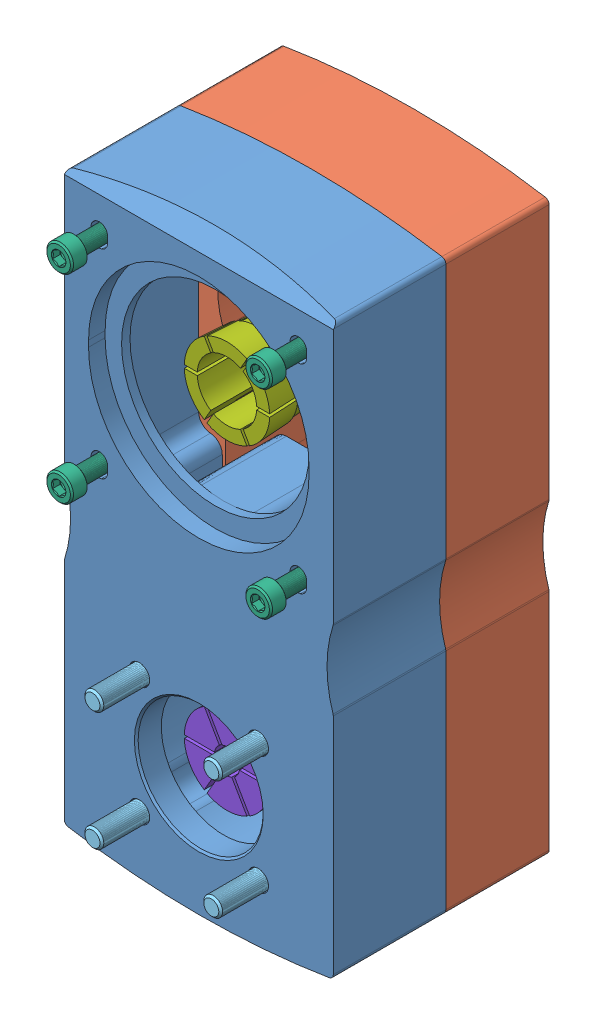
SolidWorks assembly 2802441 EAMM-U-86-D40-80P-102, configuration Default. Lengths in mm.
Overall size (86 188.5 84).
21 component instances, 8 part files, 30 mates.
Components (placement in the parent):
- 2799627 EAMM-U-86-D40-80P-102---(UT)-1: 2799627 EAMM-U-86-D40-80P-102---(UT) [Default] at (0 150.5 0) x (1 0 0) z (0 1 0) size (86 36 188.5)
- 1190018 EAMM-U-86-D40-___-188_5---(OT)-1: 1190018 EAMM-U-86-D40-___-188_5---(OT) [Default] at (0 150.5 -36) x (1 0 0) z (0 1 0) size (86 33 188.5)
- DIN-912 - M6x40(F)-1: DIN-912 - M6x40(F) [Default] at (36 -18 -62) x (1 0 0) z (0 1 0) size (10 46.29 10)
- DIN-912 - M6x40(F)-2: DIN-912 - M6x40(F) [Default] at (36 18 -62) x (1 0 0) z (0 1 0) size (10 46.29 10)
- DIN-912 - M6x40(F)-3: DIN-912 - M6x40(F) [Default] at (-36 -18 -62) x (1 0 0) z (0 1 0) size (10 46.29 10)
- DIN-912 - M6x40(F)-4: DIN-912 - M6x40(F) [Default] at (-36 18 -62) x (1 0 0) z (0 1 0) size (10 46.29 10)
- DIN-912 - M6x40(F)-5: DIN-912 - M6x40(F) [Default] at (0 143.5 -62) x (1 0 0) z (0 1 0) size (10 46.29 10)
- DIN 557 - M5-1: DIN 557 - M5 [Default] at (31.8198 134.3198 -4) x (0 0 -1) z (-0.707107 -0.707107 0) size (4 11.31 11.31)
- DIN 557 - M5-2: DIN 557 - M5 [Default] at (31.8198 70.6802 -4) x (0 0 -1) z (-0.707107 -0.707107 0) size (4 11.31 11.31)
- DIN 557 - M5-3: DIN 557 - M5 [Default] at (-31.8198 70.6802 -4) x (0 0 -1) z (-0.707107 -0.707107 0) size (4 11.31 11.31)
- DIN 557 - M5-4: DIN 557 - M5 [Default] at (-31.8198 134.3198 -4) x (0 0 -1) z (-0.707107 -0.707107 0) size (4 11.31 11.31)
- DIN-6912 - M6x18(F)-1: DIN-6912 - M6x18(F) [Default] at (19 19 -3) x (0 0 1) z (-1 0 0) size (22.29 10 10)
- DIN-6912 - M6x18(F)-2: DIN-6912 - M6x18(F) [Default] at (19 -19 -3) x (0 0 1) z (-1 0 0) size (22.29 10 10)
- DIN-6912 - M6x18(F)-3: DIN-6912 - M6x18(F) [Default] at (-19 19 -3) x (0 0 1) z (-1 0 0) size (22.29 10 10)
- DIN-6912 - M6x18(F)-4: DIN-6912 - M6x18(F) [Default] at (-19 -19 -3) x (0 0 1) z (-1 0 0) size (22.29 10 10)
- DIN-912 - M5x20(F)-1: DIN-912 - M5x20(F) [Default] at (31.8198 134.3198 8) x (1 0 0) z (0 -1 0) size (8.5 25.23 8.5)
- DIN-912 - M5x20(F)-2: DIN-912 - M5x20(F) [Default] at (31.8198 70.6802 8) x (1 0 0) z (0 -1 0) size (8.5 25.23 8.5)
- DIN-912 - M5x20(F)-3: DIN-912 - M5x20(F) [Default] at (-31.8198 70.6802 8) x (1 0 0) z (0 -1 0) size (8.5 25.23 8.5)
- DIN-912 - M5x20(F)-4: DIN-912 - M5x20(F) [Default] at (-31.8198 134.3198 8) x (1 0 0) z (0 -1 0) size (8.5 25.23 8.5)
- 2429535 EAMH-86-19-C27_3-1: 2429535 EAMH-86-19-C27_3 [Default] at (0 102.5 -49) x (0 0 1) z (-1 0 0) size (40.22 27.3 27.28)
- 2429531 EAMH-86-8-C27_3-1: 2429531 EAMH-86-8-C27_3 [Default] at (0 0 -49) x (0 0 1) z (-1 0 0) size (40.22 27.3 27.28)
Mates (geometry in assembly coordinates):
- Distance1: distance = 0 mm anti-aligned: plane of 2799627 EAMM-U-86-D40-80P-102---(UT)-1 through (0 150.5 -3) normal (0 0 -1); plane of DIN-6912 - M6x18(F)-1 through (19 19 -3) normal (0 0 1)
- Coincident1: coincident anti-aligned: line of 2799627 EAMM-U-86-D40-80P-102---(UT)-1 through (19 19 -50) axis (0 0 1); line of DIN-6912 - M6x18(F)-1 through (19 19 77.9) axis (0 0 -1)
- Angle3: planar angle = 0 rad aligned: plane of DIN-6912 - M6x18(F)-1 through (19 19 -3) normal (1 0 0); plane of 2799627 EAMM-U-86-D40-80P-102---(UT)-1 through (19 150.5 0) normal (1 0 0)
- Distance2: distance = 0 mm anti-aligned: plane of 2799627 EAMM-U-86-D40-80P-102---(UT)-1 through (0 150.5 -3) normal (0 0 -1); plane of DIN-6912 - M6x18(F)-2 through (19 -19 -3) normal (0 0 1)
- Coincident2: coincident anti-aligned: line of 2799627 EAMM-U-86-D40-80P-102---(UT)-1 through (19 -19 -50) axis (0 0 1); line of DIN-6912 - M6x18(F)-2 through (19 -19 77.9) axis (0 0 -1)
- Angle6: planar angle = 0 rad aligned: plane of DIN-6912 - M6x18(F)-2 through (19 -19 -3) normal (1 0 0); plane of 2799627 EAMM-U-86-D40-80P-102---(UT)-1 through (19 150.5 0) normal (1 0 0)
- Distance3: distance = 0 mm anti-aligned: plane of 2799627 EAMM-U-86-D40-80P-102---(UT)-1 through (0 150.5 -3) normal (0 0 -1); plane of DIN-6912 - M6x18(F)-3 through (-19 19 -3) normal (0 0 1)
- Coincident3: coincident anti-aligned: line of 2799627 EAMM-U-86-D40-80P-102---(UT)-1 through (-19 19 -50) axis (0 0 1); line of DIN-6912 - M6x18(F)-3 through (-19 19 77.9) axis (0 0 -1)
- Angle9: planar angle = 0 rad aligned: plane of DIN-6912 - M6x18(F)-3 through (-19 19 -3) normal (1 0 0); plane of 2799627 EAMM-U-86-D40-80P-102---(UT)-1 through (-19 150.5 0) normal (1 0 0)
- Distance4: distance = 0 mm anti-aligned: plane of 2799627 EAMM-U-86-D40-80P-102---(UT)-1 through (0 150.5 -3) normal (0 0 -1); plane of DIN-6912 - M6x18(F)-4 through (-19 -19 -3) normal (0 0 1)
- Coincident4: coincident anti-aligned: line of 2799627 EAMM-U-86-D40-80P-102---(UT)-1 through (-19 -19 -50) axis (0 0 1); line of DIN-6912 - M6x18(F)-4 through (-19 -19 77.9) axis (0 0 -1)
- Angle12: planar angle = 0 rad aligned: plane of DIN-6912 - M6x18(F)-4 through (-19 -19 -3) normal (1 0 0); plane of 2799627 EAMM-U-86-D40-80P-102---(UT)-1 through (-19 150.5 0) normal (1 0 0)
- Distance5: distance = 0 mm anti-aligned: plane of 2799627 EAMM-U-86-D40-80P-102---(UT)-1 through (0 150.5 8) normal (0 0 -1); plane of DIN-912 - M5x20(F)-1 through (31.8198 134.3198 8) normal (0 0 1)
- Coincident5: coincident anti-aligned: line of 2799627 EAMM-U-86-D40-80P-102---(UT)-1 through (31.8198 134.3198 -50) axis (0 0 1); line of DIN-912 - M5x20(F)-1 through (31.8198 134.3198 58) axis (0 0 -1)
- Angle15: planar angle = 0 rad aligned: plane of DIN-912 - M5x20(F)-1 through (31.8198 134.3198 8) normal (1 0 0); plane of 2799627 EAMM-U-86-D40-80P-102---(UT)-1 through (31.8198 150.5 0) normal (1 0 0)
- Distance6: distance = 0 mm anti-aligned: plane of 2799627 EAMM-U-86-D40-80P-102---(UT)-1 through (0 150.5 8) normal (0 0 -1); plane of DIN-912 - M5x20(F)-2 through (31.8198 70.6802 8) normal (0 0 1)
- Coincident6: coincident anti-aligned: line of 2799627 EAMM-U-86-D40-80P-102---(UT)-1 through (31.8198 70.6802 -50) axis (0 0 1); line of DIN-912 - M5x20(F)-2 through (31.8198 70.6802 58) axis (0 0 -1)
- Angle18: planar angle = 0 rad aligned: plane of DIN-912 - M5x20(F)-2 through (31.8198 70.6802 8) normal (1 0 0); plane of 2799627 EAMM-U-86-D40-80P-102---(UT)-1 through (31.8198 150.5 0) normal (1 0 0)
- Distance7: distance = 0 mm anti-aligned: plane of 2799627 EAMM-U-86-D40-80P-102---(UT)-1 through (0 150.5 8) normal (0 0 -1); plane of DIN-912 - M5x20(F)-3 through (-31.8198 70.6802 8) normal (0 0 1)
- Coincident7: coincident anti-aligned: line of 2799627 EAMM-U-86-D40-80P-102---(UT)-1 through (-31.8198 70.6802 -50) axis (0 0 1); line of DIN-912 - M5x20(F)-3 through (-31.8198 70.6802 58) axis (0 0 -1)
- Angle21: planar angle = 0 rad aligned: plane of DIN-912 - M5x20(F)-3 through (-31.8198 70.6802 8) normal (1 0 0); plane of 2799627 EAMM-U-86-D40-80P-102---(UT)-1 through (-31.8198 150.5 0) normal (1 0 0)
- Distance8: distance = 0 mm anti-aligned: plane of 2799627 EAMM-U-86-D40-80P-102---(UT)-1 through (0 150.5 8) normal (0 0 -1); plane of DIN-912 - M5x20(F)-4 through (-31.8198 134.3198 8) normal (0 0 1)
- Coincident8: coincident anti-aligned: line of 2799627 EAMM-U-86-D40-80P-102---(UT)-1 through (-31.8198 134.3198 -50) axis (0 0 1); line of DIN-912 - M5x20(F)-4 through (-31.8198 134.3198 58) axis (0 0 -1)
- Angle24: planar angle = 0 rad aligned: plane of DIN-912 - M5x20(F)-4 through (-31.8198 134.3198 8) normal (1 0 0); plane of 2799627 EAMM-U-86-D40-80P-102---(UT)-1 through (-31.8198 150.5 0) normal (1 0 0)
- Distance9: distance = 0 mm anti-aligned: plane of 2799627 EAMM-U-86-D40-80P-102---(UT)-1 through (0 150.5 -9) normal (0 0 -1); plane of 2429535 EAMH-86-19-C27_3-1 through (0 102.5 -9) normal (0 0 1)
- Coincident9: coincident anti-aligned: line of 2799627 EAMM-U-86-D40-80P-102---(UT)-1 through (0 102.5 -50) axis (0 0 1); line of 2429535 EAMH-86-19-C27_3-1 through (0 102.5 31.9) axis (0 0 -1)
- Angle27: planar angle = 0 rad aligned: plane of 2429535 EAMH-86-19-C27_3-1 through (0 102.5 -49) normal (1 0 0); plane of 2799627 EAMM-U-86-D40-80P-102---(UT)-1 through (0 150.5 0) normal (1 0 0)
- Distance10: distance = 0 mm anti-aligned: plane of 2799627 EAMM-U-86-D40-80P-102---(UT)-1 through (0 150.5 -9) normal (0 0 -1); plane of 2429531 EAMH-86-8-C27_3-1 through (0 0 -9) normal (0 0 1)
- Coincident10: coincident anti-aligned: line of 2799627 EAMM-U-86-D40-80P-102---(UT)-1 through (0 0 -50) axis (0 0 1); line of 2429531 EAMH-86-8-C27_3-1 through (0 0 31.9) axis (0 0 -1)
- Angle30: planar angle = 0 rad aligned: plane of 2429531 EAMH-86-8-C27_3-1 through (0 0 -49) normal (1 0 0); plane of 2799627 EAMM-U-86-D40-80P-102---(UT)-1 through (0 150.5 0) normal (1 0 0)
